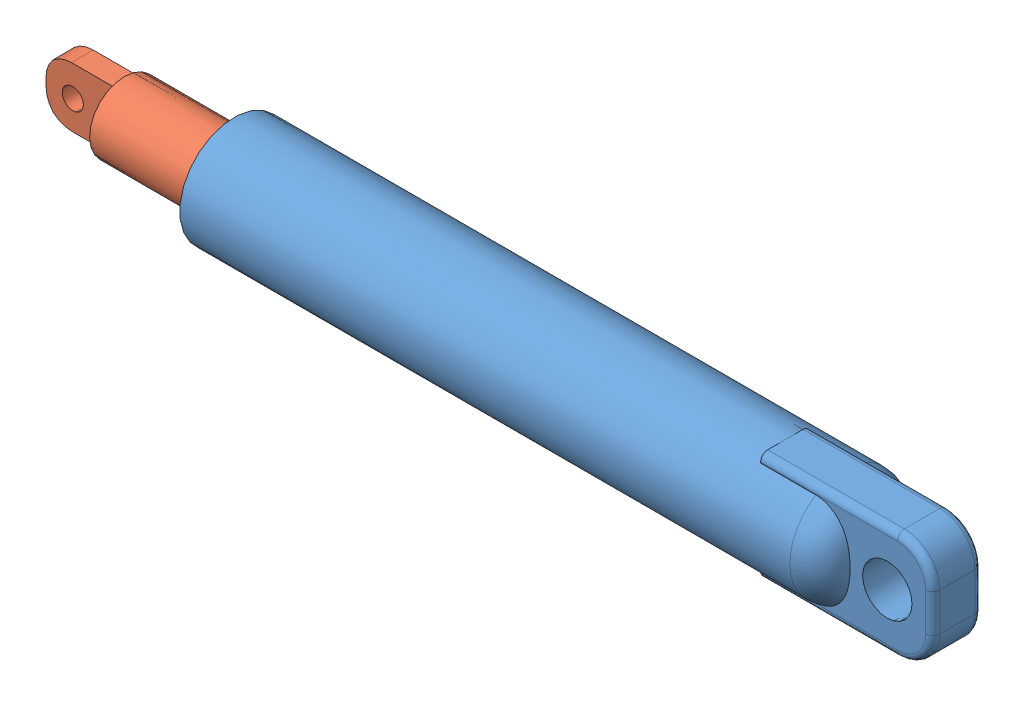
SolidWorks assembly Assem1, configuration Default. Lengths in mm.
Overall size (2356.89 282.18 282.18).
2 component instances, 2 part files, 0 mates.
Components (placement in the parent):
- Part1-1: Part1 [Default] at (-27.5678 1.4874 37.8125) size (1887.87 282.18 282.18)
- Part2-1: Part2 [Default] at (-586.2219 7.2296 32.4431) x (-0.001063 -0.999951 -0.009796) z (0.999999 -0.001064 0.000044) size (181.47 181.47 1649.7)
